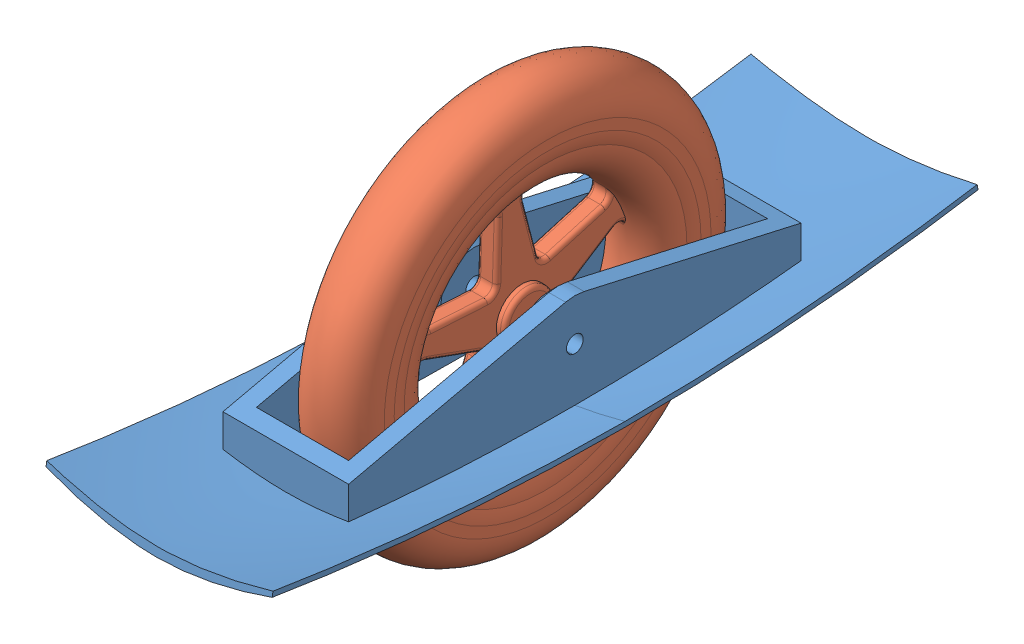
SolidWorks assembly BellyWheel, configuration Default. Lengths in mm.
Overall size (27 62.86 85).
2 component instances, 2 part files, 6 mates.
Components (placement in the parent):
- BellyPlate-1: BellyPlate [Default] x (-1 0 0) z (0 0 1) size (27 13 85)
- Wheel-1: Wheel [Default] at (0 8 0) x (1 0 0) z (0 0.911005 0.412395) size (8.5 47.5 47.5)
Mates (geometry in assembly coordinates):
- Coincident1: coincident anti-aligned: plane of BellyPlate-1; plane of assembly through (0 0 0) normal (0 1 0)
- Coincident2: coincident aligned: plane of BellyPlate-1 through (0 0 0) normal (0 0 1); plane of assembly through (0 0 0) normal (0 0 1)
- Coincident3: coincident anti-aligned: plane of BellyPlate-1; plane of assembly through (0 0 0) normal (1 0 0)
- Coincident4: coincident: line of Wheel-1 through (-7.0418 8 0) axis (1 0 0); plane of assembly
- Coincident5: coincident aligned: plane of Wheel-1; plane of assembly through (0 0 0) normal (1 0 0)
- Distance1: distance = 8 mm: line of Wheel-1 through (-7.0418 8 0) axis (1 0 0); plane of assembly
